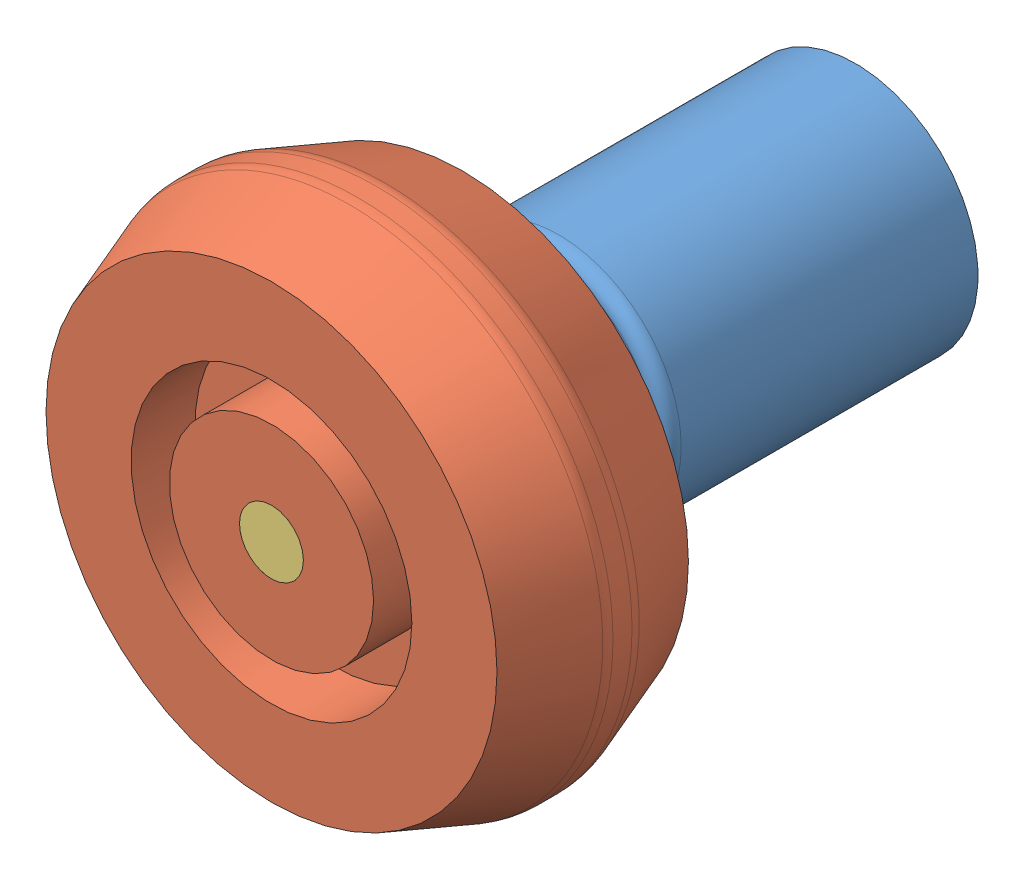
SolidWorks assembly Assem1, configuration Default. Lengths in mm.
Overall size (50.8 50.8 59).
3 component instances, 3 part files, 4 mates.
Components (placement in the parent):
- DC_Motor-1: DC_Motor [Default] at (13.1404 31.769 24.8897) size (24.38 24.38 40.49)
- Omni_Wheel-1: Omni_Wheel [Default] at (13.1404 31.769 73.4799) size (50.8 50.8 19.05)
- Motor_Coupler-1: Motor_Coupler [Default] at (13.1404 31.769 70.3049) size (6.36 6.36 25.4)
Mates (geometry in assembly coordinates):
- Concentric2: concentric anti-aligned: cylinder of Omni_Wheel-1 through (13.1404 31.769 65.2249) axis (0 0 1) radius 3.175; cylinder of Motor_Coupler-1 through (13.1404 31.769 84.2749) axis (0 0 -1) radius 3.1813
- Coincident2: coincident aligned: plane of Omni_Wheel-1 through (13.1404 31.769 84.2749) normal (0 0 1); plane of Motor_Coupler-1 through (13.1404 31.769 84.2749) normal (0 0 1)
- Concentric3: concentric aligned: cylinder of DC_Motor-1 through (13.1404 31.769 64.4883) axis (0 0 -1) radius 0.9906; cylinder of Motor_Coupler-1 through (13.1404 31.769 66.4949) axis (0 0 -1) radius 0.9843
- Distance2: distance = 1.905 mm anti-aligned: plane of Motor_Coupler-1 through (13.1404 31.769 57.6049) normal (0 0 -1); plane of DC_Motor-1 through (13.1404 31.769 55.6999) normal (0 0 1)
